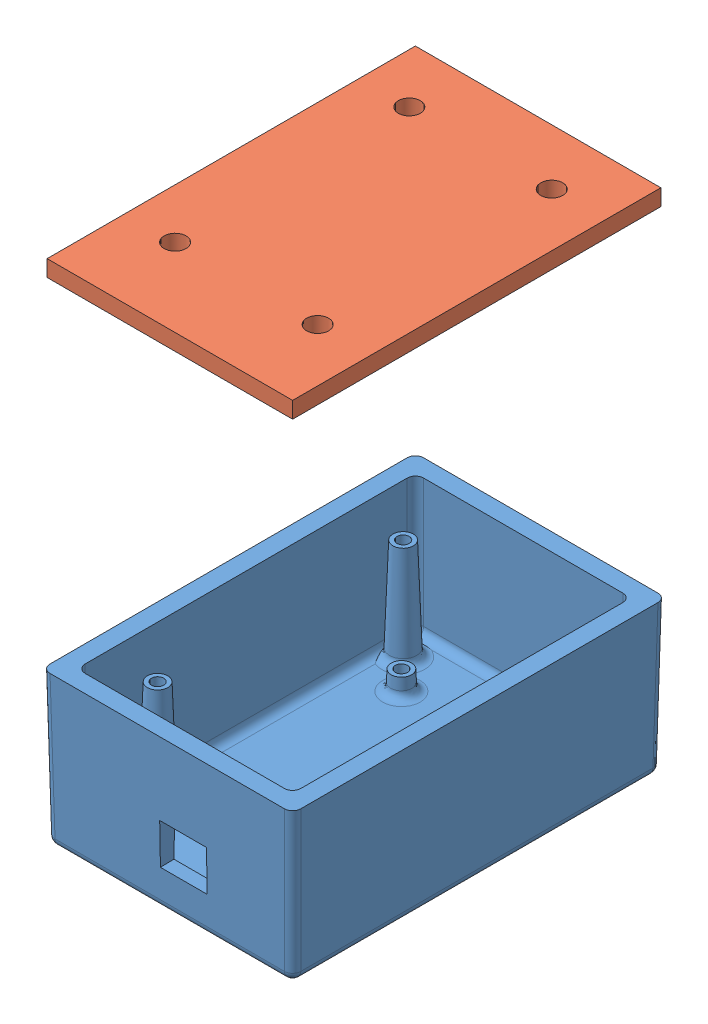
SolidWorks assembly MainController_Assem, configuration Default. Lengths in mm.
Overall size (61.29 123.79 91.29).
2 component instances, 2 part files, 0 mates.
Components (placement in the parent):
- MainController_Bottom-3: MainController_Bottom [Default] at (35.4427 51.8743 -55.8448) size (61.29 37 91.29)
- MainController_Top-3: MainController_Top [Default] at (35.4427 171.6652 -55.8448) x (-1 0 0) z (0 0 -1) size (60 14.25 90)
